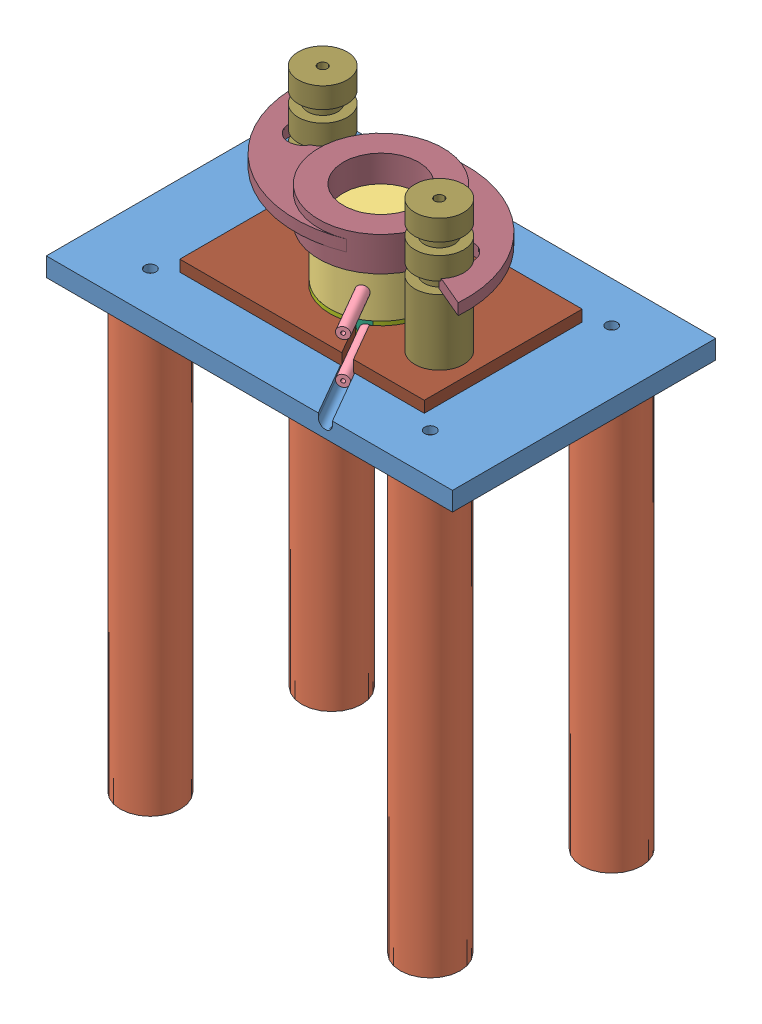
SolidWorks assembly Assembly-bioreact holder+clamp base+columns, configuration Default. Lengths in mm.
Overall size (108 158.46 98.29).
23 component instances, 13 part files, 6 mates.
Components (placement in the parent):
- Bioreactor holder-1: Bioreactor holder [Default] at (-29.8672 -32.6383 0) size (108 5 70)
- Column-1: Column [Default] at (-67.0842 -148.0983 24.1221) size (16 118.46 16)
- Column-2: Column [Default] at (7.3497 -148.0983 24.1221) size (16 118.46 16)
- Column-3: Column [Default] at (-67.0842 -148.0983 -24.1221) size (16 118.46 16)
- Column-4: Column [Default] at (7.3497 -148.0983 -24.1221) size (16 118.46 16)
- mycroscope clamp 3D + LVB1-2: mycroscope clamp 3D + LVB1 [Default] at (-33.3532 27.8985 2.0127) x (0.866025 0 -0.5) z (0.5 0 0.866025) size (77.29 43 68.87)
  - 3D view live box 1-1: 3D view live box 1 [Assemblata] at (6.7199 -46.9356 0) size (27 23 55)
    - 3Dview-Top-1: 3Dview-Top [Default] at (-2.6946 -4.6013 0) size (27 15 55)
      - Top-1: Top [Default] at origin size (27 15 27)
      - 3x1-1: 3x1 [Default] at (0 6.5 7.5) x (0.999962 0.00877 0) z (0 0 1) size (3 3 20)
      - 4x2-1: 4x2 [Default] at (0 8 -27.5) size (4 4 20)
    - 3Dview-Inner bottom-1: 3Dview-Inner bottom [Default] at (-2.6946 -11.6013 0) x (0 0 -1) z (1 0 0) size (55 6.7 21)
      - Inner bottom-1: Inner bottom [Default] at origin size (21 6.7 21)
      - 3x1-2: 3x1 [Default] at (-7.5 2.5 0) x (0 0.981723 0.190315) z (-1 0 0) size (3 3 20)
      - 3x1-4: 3x1 [Default] at (27.5 2.5 0) x (0 -0.991525 0.129918) z (-1 0 0) size (3 3 20)
    - Bottom-1: Bottom [Default] at (-2.6946 -12.6013 0) x (0 0 -1) z (1 0 0) size (27 8 27)
    - Inner up-1: Inner up [Default] at (-2.6946 -6.6013 0) size (21 4.9 21)
    - glass bottom-1: glass bottom [Default] at (-2.6946 -11.6013 0) size (21 0.3 21)
    - Membrane-1: Membrane [Default] at (-2.6946 -6.6013 0) size (19 0.1 19)
  - mycroscope clamp base-1: mycroscope clamp base [Default] at (4.0253 -60.5369 0) x (0.866025 0 0.5) z (-0.5 0 0.866025) size (65 8 42)
  - mycroscope clamp colonna-1: mycroscope clamp colonna [Default] at (-12.1415 -52.5369 -17.9942) size (13 37 13)
  - mycroscope clamp colonna-2: mycroscope clamp colonna [Default] at (20.1921 -52.5369 17.9942) size (13 37 13)
  - mycroscope clamp ali LVB1-2: mycroscope clamp ali LVB1 [Default] at (4.0253 -34.4369 0) x (0.990162 0 0.139923) z (-0.139923 0 0.990162) size (60.98 9.1 54.76)
Mates (geometry in assembly coordinates):
- Coincidente2: coincident: circle of Bioreactor holder-1; circle of Column-1
- Coincidente3: coincident: circle of Bioreactor holder-1; circle of Column-2
- Coincidente4: coincident: circle of Bioreactor holder-1; circle of Column-4
- Coincidente5: coincident: circle of Bioreactor holder-1; circle of Column-3
- Coincidente8: coincident: circle of Bioreactor holder-1; circle of mycroscope clamp 3D + LVB1-2/mycroscope clamp base-1
- Coincidente9: coincident: point of Bioreactor holder-1; point of mycroscope clamp 3D + LVB1-2/mycroscope clamp base-1
